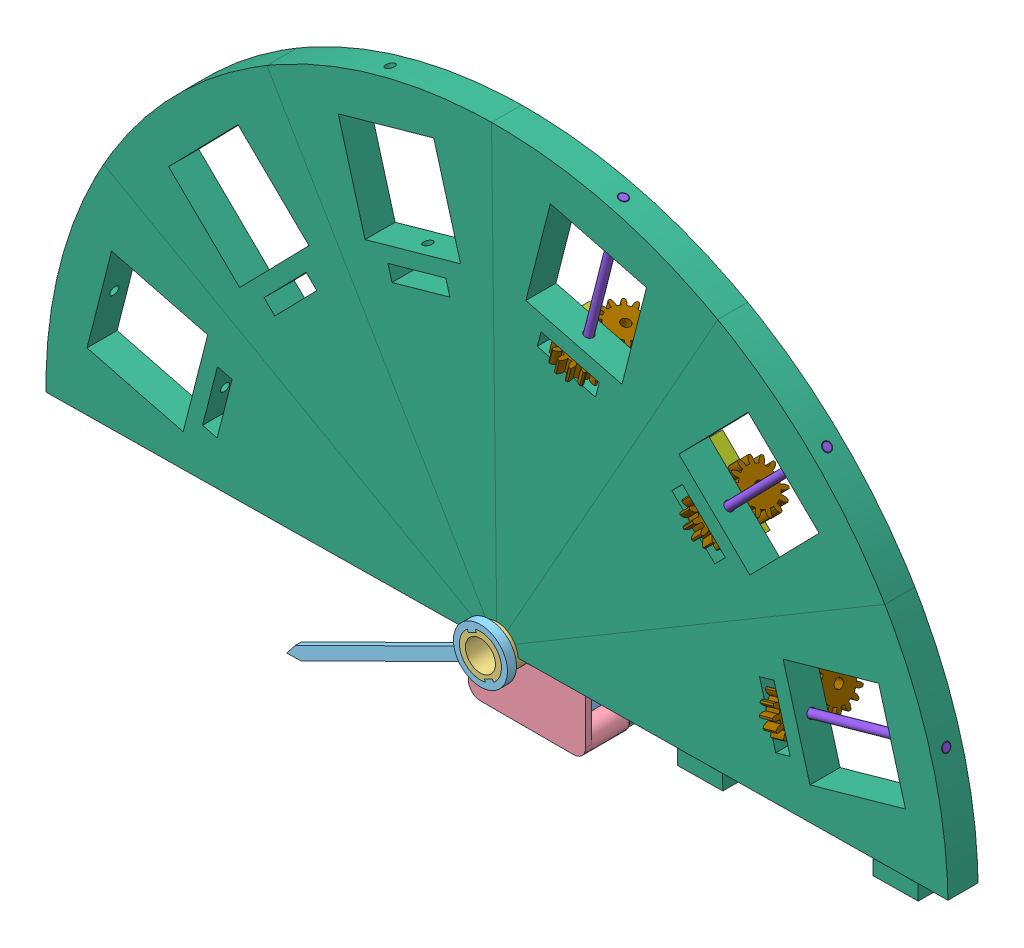
SolidWorks assembly clockhand_mount, configuration Default. Lengths in mm.
Overall size (311.52 197.64 49).
30 component instances, 9 part files, 33 mates.
Components (placement in the parent):
- stepper_28byj-48-1: stepper_28byj-48 [Default] at (6.5076 31.211 25.4875) size (38 27.6 29)
- gear_stepper_fix-1: gear_stepper_fix [Default] at (8.8896 50.3131 77.4361) x (0 0 1) z (0 -1 0) size (8 19.8 20)
- gear_hour-1: gear_hour [Default] at (13.764 50.4789 36.1175) x (0 0 -1) z (-0.444011 0.896021 0) size (24 19.8 20)
- stepper_28byj-48-2: stepper_28byj-48 [Default] at (6.5076 62.211 25.4875) x (-1 0 0) z (0 0 1) size (38 27.6 29)
- stepper_assem_frame-1: stepper_assem_frame [Default] at (6.5076 46.711 56.9875) x (-1 0 0) z (0 -1 0) size (39 17 39)
- hand_hour-1: hand_hour [Default] at (6.5076 55.711 71.4876) x (-0.444011 0.896021 0) z (0 0 1) size (18 82.06 3)
- sihverplaat_servo-1: sihverplaat_servo [Default] at (6.5076 55.711 63.9875) x (-0.962747 -0.270404 0) z (0 0 -1) size (83.42 143.29 20)
- sihverplaat_servo-2: sihverplaat_servo [Default] at (6.5076 55.711 63.9875) x (-0.698561 -0.71555 0) z (0 0 -1) size (83.42 143.29 20)
- sihverplaat_servo-3: sihverplaat_servo [Default] at (6.5076 55.711 63.9875) x (-0.247196 -0.968965 0) z (0 0 -1) size (83.42 143.29 20)
- servo-1: servo [Default] at (-69.1015 68.8077 58.9875) x (-0.247196 -0.968965 0) z (0 0 -1) size (30 31 12)
- servo-2: servo [Default] at (-52.4234 104.8576 58.9875) x (-0.698561 -0.71555 0) z (0 0 -1) size (30 31 12)
- servo-3: servo [Default] at (-20.4362 127.6035 58.9875) x (-0.962747 -0.270404 0) z (0 0 -1) size (30 31 12)
- proto_servo-1: proto_servo [Default] at (-30.6976 -119.1224 334.7415) x (-0.968965 0.247196 0) z (0 0 -1) size (83.42 143.29 33.73)
  - sihverplaat_servo-1: sihverplaat_servo [Default] at (7.1676 178.6045 270.754) size (83.42 143.29 20)
  - numbriplaat_shaft-1: numbriplaat_shaft [Default] at (7.1676 268.6607 270.754) size (2.6 60 2.6)
  - spur gear_am-6: spur gear_am [Metric - Spur gear 1M 14T 14.5PA 4.5mmFW ---S14N75H50L3N] at (7.1676 272.6045 270.754) x (0 1 0) z (0.994793 0 -0.101917) size (4.5 15.72 16)
  - spur gear_am-8: spur gear_am [Metric - Spur gear 1M 14T 14.5PA 4.5mmFW ---S14N75H50L3N] at (7.6676 277.1045 284.754) x (0 -1 0) z (-0.79797 0 0.602697) size (4.5 15.72 16)
  - servo-1: servo [Default] at (12.6676 255.1045 278.754) size (30 31 12)
- proto_servo-2: proto_servo [Default] at (-113.1298 -77.0966 334.7415) x (-0.71555 0.698561 0) z (0 0 -1) size (83.42 143.29 33.73)
  - sihverplaat_servo-1: sihverplaat_servo [Default] at (7.1676 178.6045 270.754) size (83.42 143.29 20)
  - numbriplaat_shaft-1: numbriplaat_shaft [Default] at (7.1676 268.6607 270.754) size (2.6 60 2.6)
  - spur gear_am-6: spur gear_am [Metric - Spur gear 1M 14T 14.5PA 4.5mmFW ---S14N75H50L3N] at (7.1676 272.6045 270.754) x (0 1 0) z (0.994793 0 -0.101917) size (4.5 15.72 16)
  - spur gear_am-8: spur gear_am [Metric - Spur gear 1M 14T 14.5PA 4.5mmFW ---S14N75H50L3N] at (7.6676 277.1045 284.754) x (0 -1 0) z (-0.79797 0 0.602697) size (4.5 15.72 16)
  - servo-1: servo [Default] at (12.6676 255.1045 278.754) size (30 31 12)
- proto_servo-3: proto_servo [Default] at (-163.5052 0.5149 334.7415) x (-0.270404 0.962747 0) z (0 0 -1) size (83.42 143.29 33.73)
  - sihverplaat_servo-1: sihverplaat_servo [Default] at (7.1676 178.6045 270.754) size (83.42 143.29 20)
  - numbriplaat_shaft-1: numbriplaat_shaft [Default] at (7.1676 268.6607 270.754) size (2.6 60 2.6)
  - spur gear_am-6: spur gear_am [Metric - Spur gear 1M 14T 14.5PA 4.5mmFW ---S14N75H50L3N] at (7.1676 272.6045 270.754) x (0 1 0) z (0.994793 0 -0.101917) size (4.5 15.72 16)
  - spur gear_am-8: spur gear_am [Metric - Spur gear 1M 14T 14.5PA 4.5mmFW ---S14N75H50L3N] at (7.6676 277.1045 284.754) x (0 -1 0) z (-0.79797 0 0.602697) size (4.5 15.72 16)
  - servo-1: servo [Default] at (12.6676 255.1045 278.754) size (30 31 12)
Mates (geometry in assembly coordinates):
- Coincident1: coincident anti-aligned: plane of stepper_28byj-48-1 through (6.5076 39.211 48.4875) normal (0 1 0); plane of gear_stepper_fix-1 through (8.8896 39.211 60.6106) normal (0 -1 0)
- Coincident2: coincident anti-aligned: plane of stepper_28byj-48-1 through (6.5076 31.211 48.4875) normal (0 0 1); plane of gear_stepper_fix-1 through (6.5076 37.711 48.4875) normal (0 0 -1)
- Concentric1: concentric aligned: circle of stepper_28byj-48-1; circle of gear_stepper_fix-1
- Coincident4: coincident aligned: plane of gear_stepper_fix-1 through (6.5076 37.711 50.4875) normal (0 0 -1); plane of gear_hour-1 through (6.5076 55.711 50.4875) normal (0 0 -1)
- Coincident5: coincident aligned: plane of stepper_28byj-48-1 through (6.5076 31.211 25.4875) normal (0 0 -1); plane of stepper_28byj-48-2 through (6.5076 62.211 25.4875) normal (0 0 -1)
- Concentric3: concentric anti-aligned: circle of gear_hour-1; circle of stepper_28byj-48-2
- Parallel2: parallel anti-aligned: plane of stepper_28byj-48-1 through (-8.9924 34.711 43.6875) normal (0 1 0); plane of stepper_28byj-48-2 through (22.0076 58.711 43.6875) normal (0 -1 0)
- Parallel3: parallel anti-aligned: line of stepper_28byj-48-1 through (13.6076 17.611 28.1875) axis (-1 0 0); line of stepper_28byj-48-2 through (-0.5924 75.811 28.1875) axis (1 0 0)
- Coincident9: coincident anti-aligned: line of stepper_28byj-48-1 through (13.6076 17.611 28.1875) axis (0 1 0); line of stepper_28byj-48-2 through (13.6076 75.811 28.1875) axis (0 -1 0)
- Concentric4: concentric anti-aligned: circle of stepper_assem_frame-1; circle of stepper_28byj-48-2
- Concentric6: concentric anti-aligned: cylinder of stepper_28byj-48-1; cylinder of stepper_assem_frame-1 through (-8.9924 31.211 58.9875) axis (0 0 -1) radius 4
- Coincident11: coincident anti-aligned: plane of stepper_28byj-48-1 through (6.5076 31.211 44.4875) normal (0 0 1); plane of stepper_assem_frame-1 through (6.5076 46.711 44.4875) normal (0 0 -1)
- Concentric7: concentric aligned: circle of gear_hour-1; circle of hand_hour-1
- Coincident12: coincident aligned: plane of gear_hour-1 through (6.5076 55.711 74.4876) normal (0 0 1); plane of hand_hour-1 through (6.5076 55.711 74.4876) normal (0 0 1)
- Coincident13: coincident aligned: line of gear_hour-1 through (10.5157 51.0008 74.4876) axis (-0.896021 -0.444011 0); line of hand_hour-1 through (10.5157 51.0008 74.4876) axis (-0.896021 -0.444011 0)
- Coincident14: coincident anti-aligned: plane of sihverplaat_servo-1 through (15.1071 60.8146 63.9875) normal (-0.859956 -0.510368 0); plane of sihverplaat_servo-2 through (15.1071 60.8146 63.9875) normal (0.859956 0.510368 0)
- Coincident15: coincident anti-aligned: plane of sihverplaat_servo-1 through (6.5076 55.711 63.9875) normal (0 0 -1); plane of sihverplaat_servo-2 through (6.5076 55.711 63.9875) normal (0 0 1)
- Coincident16: coincident anti-aligned: plane of sihverplaat_servo-1 through (-62.3921 171.8051 63.9875) normal (0.510368 -0.859956 0); plane of sihverplaat_servo-2 through (-62.3921 171.8051 63.9875) normal (-0.510368 0.859956 0)
- Coincident17: coincident anti-aligned: plane of stepper_assem_frame-1 through (6.5076 46.711 58.9875) normal (0 0 1); plane of sihverplaat_servo-2 through (6.5076 55.711 58.9875) normal (0 0 -1)
- Concentric8: concentric aligned: cylinder of gear_hour-1 through (6.5076 55.711 74.4876) axis (0 0 -1) radius 7; cylinder of sihverplaat_servo-1 through (6.5076 55.711 68.9875) axis (0 0 -1) radius 7
- Coincident18: coincident aligned: circle of sihverplaat_servo-2; circle of sihverplaat_servo-3
- Coincident19: coincident anti-aligned: plane of sihverplaat_servo-2 through (11.4032 64.4307 63.9875) normal (-0.48956 -0.87197 0); plane of sihverplaat_servo-3 through (11.4032 64.4307 63.9875) normal (0.48956 0.87197 0)
- Coincident21: coincident anti-aligned: plane of sihverplaat_servo-3 through (-73.4321 76.1047 48.9875) normal (-0.968965 0.247196 0); plane of servo-1 through (-78.6232 55.7564 58.9875) normal (0.968965 -0.247196 0)
- Coincident22: coincident anti-aligned: plane of sihverplaat_servo-3 through (6.5076 55.711 58.9875) normal (0 0 -1); plane of servo-1 through (-69.1015 68.8077 58.9875) normal (0 0 1)
- Coincident23: coincident anti-aligned: plane of sihverplaat_servo-3 through (7.7436 60.5558 48.9875) normal (-0.247196 -0.968965 0); plane of servo-1 through (-54.7547 76.5 46.9875) normal (0.247196 0.968965 0)
- Coincident24: coincident anti-aligned: plane of sihverplaat_servo-2 through (6.5076 55.711 58.9875) normal (0 0 -1); plane of servo-2 through (-52.4234 104.8576 58.9875) normal (0 0 1)
- Coincident25: coincident anti-aligned: plane of sihverplaat_servo-2 through (10.0004 59.2887 48.9875) normal (-0.698561 -0.71555 0); plane of servo-2 through (-36.1526 104.3459 46.9875) normal (0.698561 0.71555 0)
- Coincident26: coincident anti-aligned: plane of sihverplaat_servo-2 through (-52.5253 113.3422 48.9875) normal (-0.71555 0.698561 0); plane of servo-2 through (-67.1951 98.3157 58.9875) normal (0.71555 -0.698561 0)
- Coincident29: coincident anti-aligned: plane of sihverplaat_servo-1 through (6.5076 55.711 58.9875) normal (0 0 -1); plane of servo-3 through (-20.4362 127.6035 58.9875) normal (0 0 1)
- Coincident30: coincident anti-aligned: plane of sihverplaat_servo-1 through (-10.3405 50.9789 48.9875) normal (0.962747 0.270404 0); plane of servo-3 through (-27.7816 113.0761 46.9875) normal (-0.962747 -0.270404 0)
- Coincident31: coincident anti-aligned: plane of sihverplaat_servo-1 through (-15.8008 135.1376 48.9875) normal (-0.270404 0.962747 0); plane of servo-3 through (-36.4998 129.3239 58.9875) normal (0.270404 -0.962747 0)
- Coincident36: coincident aligned: circle of sihverplaat_servo-1; circle of proto_servo-1/sihverplaat_servo-1
- Coincident37: coincident anti-aligned: plane of sihverplaat_servo-1 through (6.5076 55.711 68.9875) normal (0.999928 0.012013 0); plane of proto_servo-1/sihverplaat_servo-1 through (6.5076 55.711 68.9875) normal (-0.999928 -0.012013 0)
